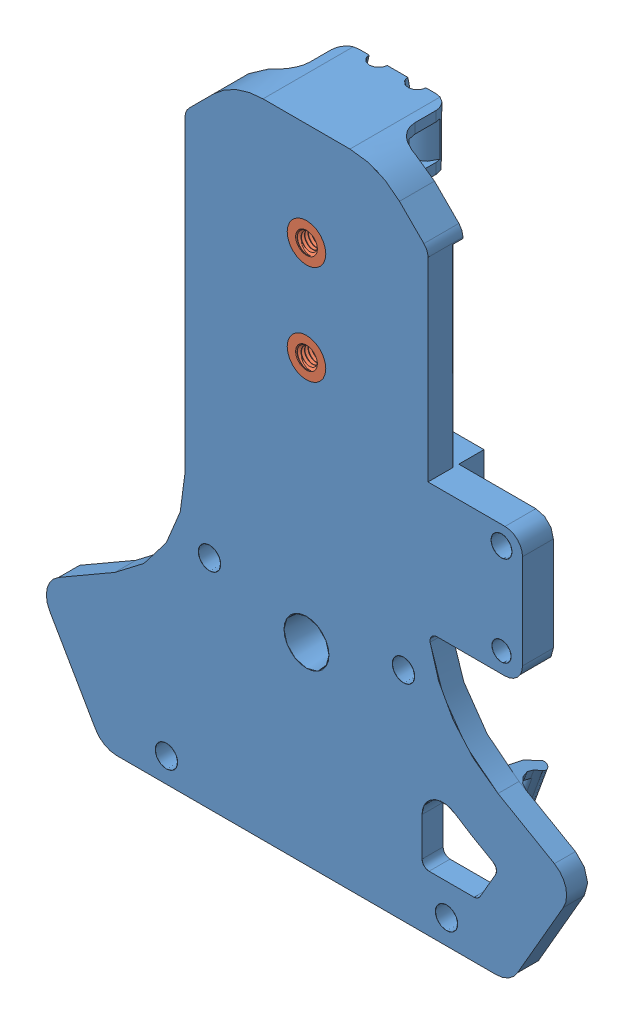
SolidWorks assembly carriage_back_plate_with_inserts, configuration Default. Lengths in mm.
Overall size (74.3 91.67 58.89).
5 component instances, 2 part files, 8 mates.
Components (placement in the parent):
- carriage_9mm_belt-1: carriage_9mm_belt [Carriage Back Plate] at (97.5575 375.4795 75.9434) size (74.3 91.67 58.89)
- m3_heat_set_insert_94180A331-1: m3_heat_set_insert_94180A331 [94180A331] at (97.5575 424.8795 42.1434) x (0.303083 -0.952964 0) z (-0.952964 -0.303083 0) size (5.56 4.12 5.56)
- m3_heat_set_insert_94180A331-2: m3_heat_set_insert_94180A331 [94180A331] at (97.5575 410.6795 42.1434) x (0.303083 -0.952964 0) z (-0.952964 -0.303083 0) size (5.56 4.12 5.56)
- m3_heat_set_insert_94180A331-3: m3_heat_set_insert_94180A331 [94180A331] at (102.9075 399.4295 34.1434) x (-0.000984 -1 0) z (1 -0.000984 0) size (5.56 4.12 5.56)
- m3_heat_set_insert_94180A331-4: m3_heat_set_insert_94180A331 [94180A331] at (92.2075 399.4295 34.1434) x (-0.000984 -1 0) z (1 -0.000984 0) size (5.56 4.12 5.56)
Mates (geometry in assembly coordinates):
- Coincident1594070846: coincident aligned: plane of carriage_9mm_belt-1 through (134.9075 387.7667 42.1434) normal (0 0 1); plane of m3_heat_set_insert_94180A331-1 through (97.5575 424.8795 42.1434) normal (0 0 1)
- Coincident1594070847: coincident aligned: plane of carriage_9mm_belt-1 through (134.9075 387.7667 42.1434) normal (0 0 1); plane of m3_heat_set_insert_94180A331-2 through (97.5575 410.6795 42.1434) normal (0 0 1)
- Coincident1594070848: coincident aligned: plane of carriage_9mm_belt-1 through (114.9075 432.5895 34.1434) normal (0 0 -1); plane of m3_heat_set_insert_94180A331-3 through (102.9075 399.4295 34.1434) normal (0 0 -1)
- Coincident1594070849: coincident aligned: plane of carriage_9mm_belt-1 through (114.9075 432.5895 34.1434) normal (0 0 -1); plane of m3_heat_set_insert_94180A331-4 through (92.2075 399.4295 34.1434) normal (0 0 -1)
- Concentric1: concentric aligned: cylinder of carriage_9mm_belt-1 through (102.9075 399.4295 49.3559) axis (0 0 -1) radius 2.55; circle of m3_heat_set_insert_94180A331-3
- Concentric2: concentric aligned: cylinder of carriage_9mm_belt-1 through (92.2075 399.4295 49.3559) axis (0 0 -1) radius 2.55; cylinder of m3_heat_set_insert_94180A331-4 through (92.2075 399.4295 34.1434) axis (0 0 -1) radius 2.58
- Concentric3: concentric anti-aligned: cylinder of carriage_9mm_belt-1 through (97.5575 424.8795 38.3434) axis (0 0 -1) radius 2.525; cylinder of m3_heat_set_insert_94180A331-1 through (97.5575 424.8795 42.1434) axis (0 0 1) radius 2.58
- Concentric4: concentric anti-aligned: cylinder of carriage_9mm_belt-1 through (97.5575 410.6795 38.3434) axis (0 0 -1) radius 2.525; cylinder of m3_heat_set_insert_94180A331-2 through (97.5575 410.6795 42.1434) axis (0 0 1) radius 2.58
